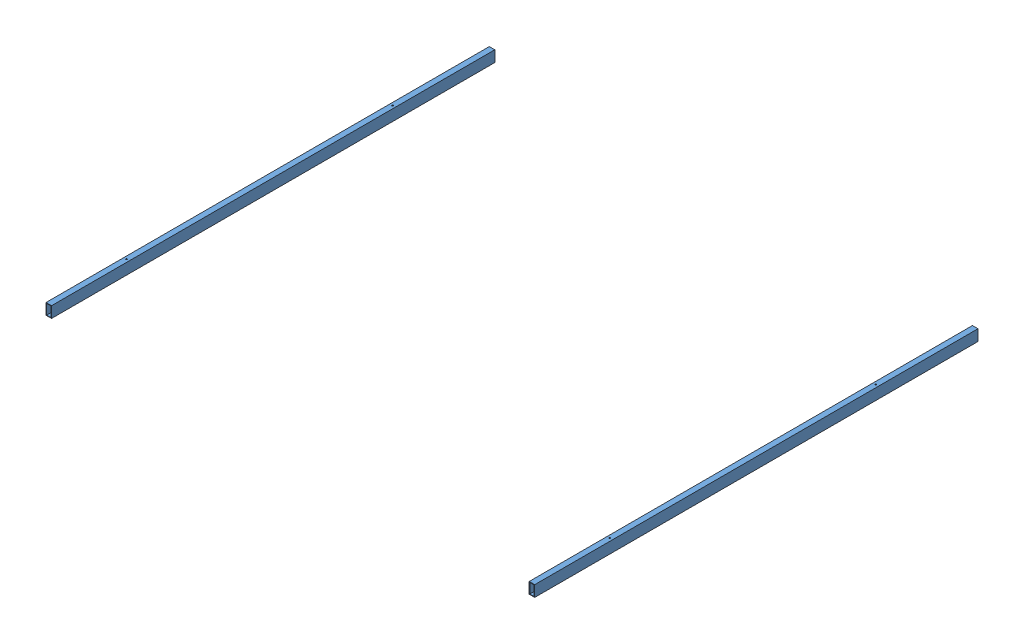
SolidWorks assembly charpente, configuration Défaut. Lengths in mm.
Overall size (2205 50 2000).
2 component instances, 1 part files, 3 mates.
Components (placement in the parent):
- barre charpeinte-1: barre charpeinte [Défaut] at (-16.4034 -3.739 1000) size (25 50 2000)
- barre charpeinte-2: barre charpeinte [Défaut] at (2163.5966 -3.739 1000) size (25 50 2000)
Mates (geometry in assembly coordinates):
- Coïncidente1: coincident anti-aligned: plane of barre charpeinte-2 through (2176.0966 -28.739 3000) normal (1 0 0)
- Coïncidente2: coincident aligned: plane of barre charpeinte-1 through (-28.9034 21.261 3000) normal (0 1 0); plane of barre charpeinte-2 through (2151.0966 21.261 3000) normal (0 1 0)
- Coïncidente3: coincident aligned: plane of barre charpeinte-1 through (-16.4034 -3.739 3000) normal (0 0 1); plane of barre charpeinte-2 through (2163.5966 -3.739 3000) normal (0 0 1)
